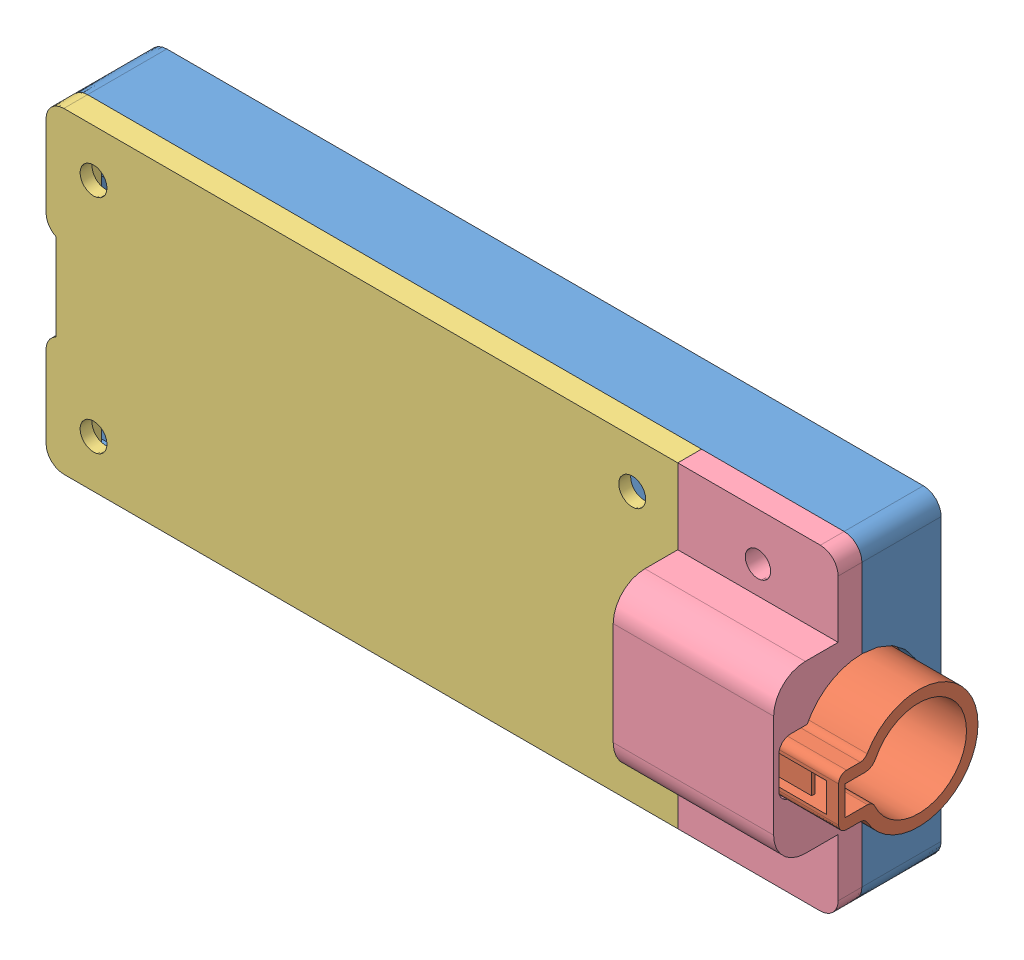
SolidWorks assembly Assem1, configuration Default. Lengths in mm.
Overall size (107.25 40 21.15).
4 component instances, 4 part files, 9 mates.
Components (placement in the parent):
- etna-long-1: etna-long [Default] at (8.1225 48.1056 92.3032) size (100 40 10)
- RPC1-12RB-6P-1: RPC1-12RB-6P [Default] at (105.8725 68.1056 102.4032) x (0 -1 0) z (-1 0 0) size (20.2 20.2 22.2)
- etna-top-ling-1: etna-top-ling [Default] at (8.1225 48.1056 102.3032) size (79.75 40 3.7)
- etna-cover-1: etna-cover [Default] at (87.8725 48.1056 102.3032) size (20.25 40 11.15)
Mates (geometry in assembly coordinates):
- Width1: width anti-aligned: plane of RPC1-12RB-6P-1 through (103.8725 68.1056 102.4032) normal (-1 0 0); plane of RPC1-12RB-6P-1 through (105.8725 68.1056 102.4032) normal (1 0 0); plane of etna-long-1 through (103.6225 78.3556 92.3032) normal (1 0 0); plane of etna-long-1 through (106.1225 78.3556 92.3032) normal (-1 0 0)
- Width2: width aligned: plane of RPC1-12RB-6P-1 through (105.8725 58.0056 109.6532) normal (0 -1 0); plane of RPC1-12RB-6P-1 through (105.8725 78.2056 95.1532) normal (0 1 0); plane of etna-long-1 through (103.6225 78.3556 92.3032) normal (0 -1 0); plane of etna-long-1 through (103.6225 57.8556 92.3032) normal (0 1 0)
- Coincident2: coincident aligned: plane of etna-long-1 through (8.1225 48.1056 92.3032) normal (0 0 -1); plane of RPC1-12RB-6P-1 through (105.8725 60.8556 92.3032) normal (0 0 -1)
- Coincident6: coincident anti-aligned: plane of etna-long-1 through (8.1225 48.1056 102.3032) normal (0 0 1); plane of etna-top-ling-1 through (8.1225 48.1056 102.3032) normal (0 0 -1)
- Coincident7: coincident aligned: plane of etna-long-1 through (8.1225 62.8556 102.3032) normal (-1 0 0); plane of etna-top-ling-1 through (8.1225 48.1056 105.3032) normal (-1 0 0)
- Coincident8: coincident aligned: plane of etna-long-1 through (8.1225 48.1056 102.3032) normal (0 -1 0); plane of etna-top-ling-1 through (8.1225 48.1056 105.3032) normal (0 -1 0)
- Coincident9: coincident anti-aligned: plane of etna-long-1 through (8.1225 48.1056 102.3032) normal (0 0 1); plane of etna-cover-1 through (87.8725 48.1056 102.3032) normal (0 0 -1)
- Coincident10: coincident aligned: plane of etna-long-1 through (108.1225 48.1056 102.3032) normal (1 0 0); plane of etna-cover-1 through (108.1225 48.1056 105.3032) normal (1 0 0)
- Coincident11: coincident aligned: plane of etna-long-1 through (8.1225 48.1056 102.3032) normal (0 -1 0); plane of etna-cover-1 through (87.8725 48.1056 105.3032) normal (0 -1 0)
